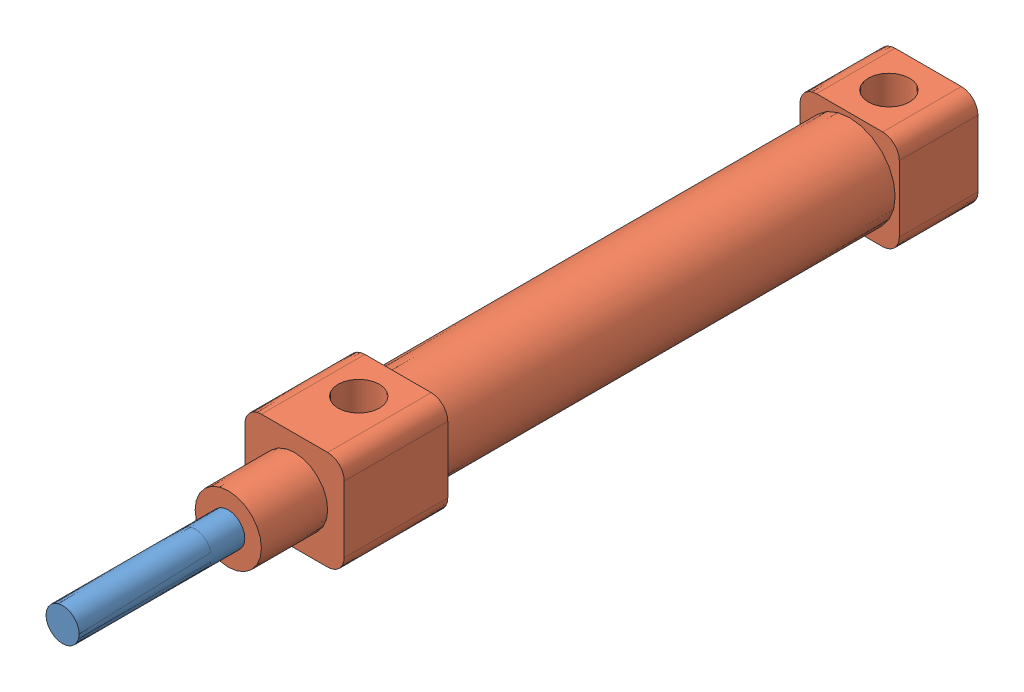
SolidWorks assembly 10x30标准型, configuration 默认. Lengths in mm.
Overall size (12 12 104.5).
2 component instances, 2 part files, 2 mates.
Components (placement in the parent):
- 10x30标准型-杆-1: 10x30标准型-杆 [默认] at (15.7001 -12.3638 412.9304) size (4 4 94)
- 10x30标准型-壳-2: 10x30标准型-壳 [默认] at (15.7001 -12.3638 402.4304) size (12 12 84.5)
Mates (geometry in assembly coordinates):
- 同心1: concentric: cylinder of assembly; cylinder of assembly; cylinder of 10x30标准型-杆-1 through (15.7001 -12.3638 506.9304) axis (0 0 -1) radius 2; cylinder of 10x30标准型-壳-2 through (15.7001 -12.3638 396.7735) axis (0 0 1) radius 2
- LimitDistance1: limit distance = 20 mm: plane of assembly; plane of assembly; plane of 10x30标准型-壳-2 through (15.7001 -12.3638 486.9304) normal (0 0 1); plane of 10x30标准型-杆-1 through (15.7001 -12.3638 506.9304) normal (0 0 1)
